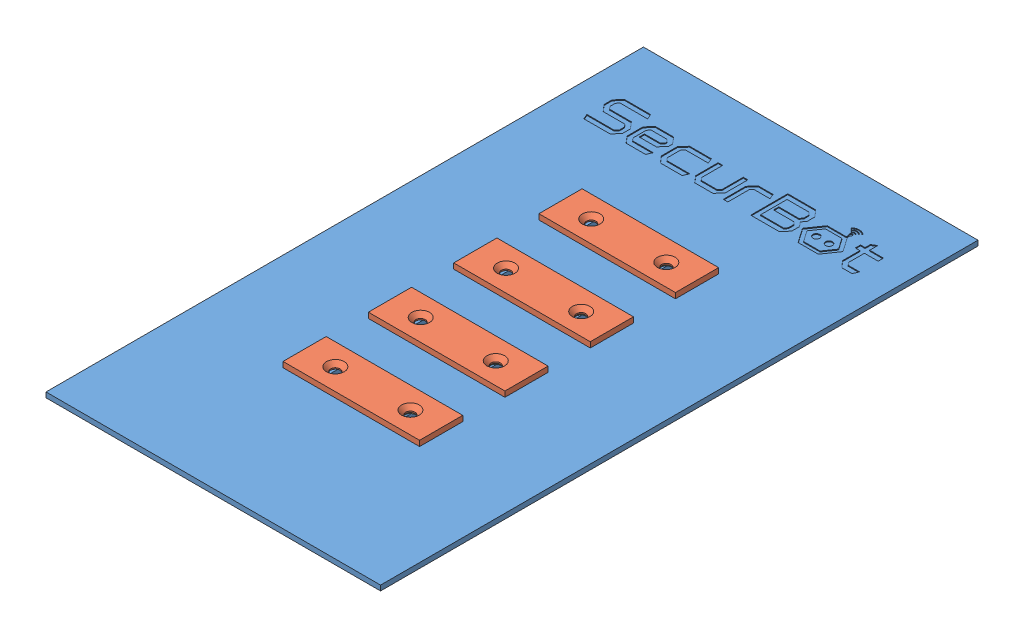
SolidWorks assembly Front_Panel_aluminiumContact, configuration Default. Lengths in mm.
Overall size (196 15.57 350).
17 component instances, 4 part files, 21 mates.
Components (placement in the parent):
- Body_Front_panel_aluContact_Pioneer-1: Body_Front_panel_aluContact_Pioneer [Default] at (76.7034 217.7564 486.4907) size (196 3 350)
- ContactAluFer-1: ContactAluFer [Default] at (200.8005 260.6088 326.6446) x (-1 0 0) z (0 0 1) size (80 15.57 25.3)
  - Contact_barreAlu-1: Contact_barreAlu [Default] at (-13.9029 35.8024 53.6961) size (80 3.2 25.3)
  - ConnecteurAAnneau-1: ConnecteurAAnneau [Default] at (4.0971 39.0024 66.3461) x (0 0 1) z (-1 0 0) size (11.92 12.37 20.64)
  - Contact_barreFer-1: Contact_barreFer [Default] at (-3.9029 42.8524 75.6811) size (60 3.15 18.67)
- ContactAluFer-2: ContactAluFer [Default] at (200.8005 260.6088 226.6379) x (-1 0 0) z (0 0 1) size (80 15.57 25.3)
  - Contact_barreAlu-1: Contact_barreAlu [Default] at (-13.9029 35.8024 53.6961) size (80 3.2 25.3)
  - ConnecteurAAnneau-1: ConnecteurAAnneau [Default] at (4.0971 39.0024 66.3461) x (0 0 1) z (-1 0 0) size (11.92 12.37 20.64)
  - Contact_barreFer-1: Contact_barreFer [Default] at (-3.9029 42.8524 75.6811) size (60 3.15 18.67)
- ContactAluFer-3: ContactAluFer [Default] at (200.8005 260.6088 276.6446) x (-1 0 0) z (0 0 1) size (80 15.57 25.3)
  - Contact_barreAlu-1: Contact_barreAlu [Default] at (-13.9029 35.8024 53.6961) size (80 3.2 25.3)
  - ConnecteurAAnneau-1: ConnecteurAAnneau [Default] at (4.0971 39.0024 66.3461) x (0 0 1) z (-1 0 0) size (11.92 12.37 20.64)
  - Contact_barreFer-1: Contact_barreFer [Default] at (-3.9029 42.8524 75.6811) size (60 3.15 18.67)
- ContactAluFer-4: ContactAluFer [Default] at (200.8005 260.6088 176.7387) x (-1 0 0) z (0 0 1) size (80 15.57 25.3)
  - Contact_barreAlu-1: Contact_barreAlu [Default] at (-13.9029 35.8024 53.6961) size (80 3.2 25.3)
  - ConnecteurAAnneau-1: ConnecteurAAnneau [Default] at (4.0971 39.0024 66.3461) x (0 0 1) z (-1 0 0) size (11.92 12.37 20.64)
  - Contact_barreFer-1: Contact_barreFer [Default] at (-3.9029 42.8524 75.6811) size (60 3.15 18.67)
Mates (geometry in assembly coordinates):
- Coincident2: coincident anti-aligned: plane of Side_court_avant-1 through (76.7034 220.7564 486.4907) normal (0 1 0); plane of Base_of_box_onpioneer-1 through (111.4034 220.7564 376.4907) normal (0 -1 0)
- Parallel1: parallel aligned: line of Side_court_avant-1 through (76.7034 220.7564 486.4907) axis (1 0 0); line of Base_of_box_onpioneer-1 through (111.4034 220.7564 416.4907) axis (1 0 0)
- Coincident4: coincident anti-aligned: line of Base_of_box_onpioneer-1 through (111.4034 220.7564 416.4907) axis (1 0 0)
- Coincident7: coincident: line of Base_of_box_onpioneer-1 through (174.7034 225.7564 416.4907) axis (0 -1 0)
- Parallel2: parallel aligned: line of Base_of_box_onpioneer-1 through (238.0034 225.7564 416.4907) axis (-1 0 0)
- Coincident20: coincident: unknown of Contact-4
- Parallel3: parallel anti-aligned: line of Contact-4/Part1_contact-1 through (114.7034 220.7564 261.2407) axis (1 0 0)
- Coincident21: coincident anti-aligned: plane of Side_court_avant-1 through (76.7034 220.7564 486.4907) normal (0 1 0); plane of Contact-4/Part1_contact-1 through (134.7034 220.7564 256.2407) normal (0 -1 0)
- Coincident22: coincident: point of ContactAluFer-1/Contact_barreFer-1; point of assembly
- Coincident23: coincident anti-aligned: plane of Side_court_avant-1 through (76.7034 217.7564 486.4907) normal (0 -1 0); plane of ContactAluFer-1/Contact_barreFer-1 through (204.7034 217.7564 402.3257) normal (0 1 0)
- Parallel4: parallel anti-aligned: line of ContactAluFer-1/Contact_barreFer-1 through (144.7034 217.7564 392.9907) axis (1 0 0)
- Coincident24: coincident: unknown of ContactAluFer-3/Contact_barreFer-1
- Coincident25: coincident: unknown of ContactAluFer-2/Contact_barreFer-1
- Coincident26: coincident: unknown of ContactAluFer-4/Contact_barreFer-1
- Coincident27: coincident anti-aligned: plane of Side_court_avant-1 through (76.7034 217.7564 486.4907) normal (0 -1 0); plane of ContactAluFer-4/Contact_barreFer-1 through (204.7034 217.7564 252.4198) normal (0 1 0)
- Coincident28: coincident anti-aligned: plane of Side_court_avant-1 through (76.7034 217.7564 486.4907) normal (0 -1 0); plane of ContactAluFer-2/Contact_barreFer-1 through (204.7034 217.7564 302.319) normal (0 1 0)
- Coincident29: coincident anti-aligned: plane of Side_court_avant-1 through (76.7034 217.7564 486.4907) normal (0 -1 0); plane of ContactAluFer-3/Contact_barreFer-1 through (204.7034 217.7564 352.3257) normal (0 1 0)
- Parallel5: parallel anti-aligned: line of ContactAluFer-3/Contact_barreFer-1 through (144.7034 217.7564 342.9907) axis (1 0 0)
- Parallel6: parallel anti-aligned: line of ContactAluFer-2/Contact_barreFer-1 through (144.7034 217.7564 292.984) axis (1 0 0)
- Parallel7: parallel anti-aligned: line of ContactAluFer-4/Contact_barreFer-1 through (144.7034 217.7564 243.0848) axis (1 0 0)
- Parallel8: parallel aligned: line of ContactAluFer-1/Contact_barreFer-1 through (204.7034 214.6064 402.3257) axis (-1 0 0)
